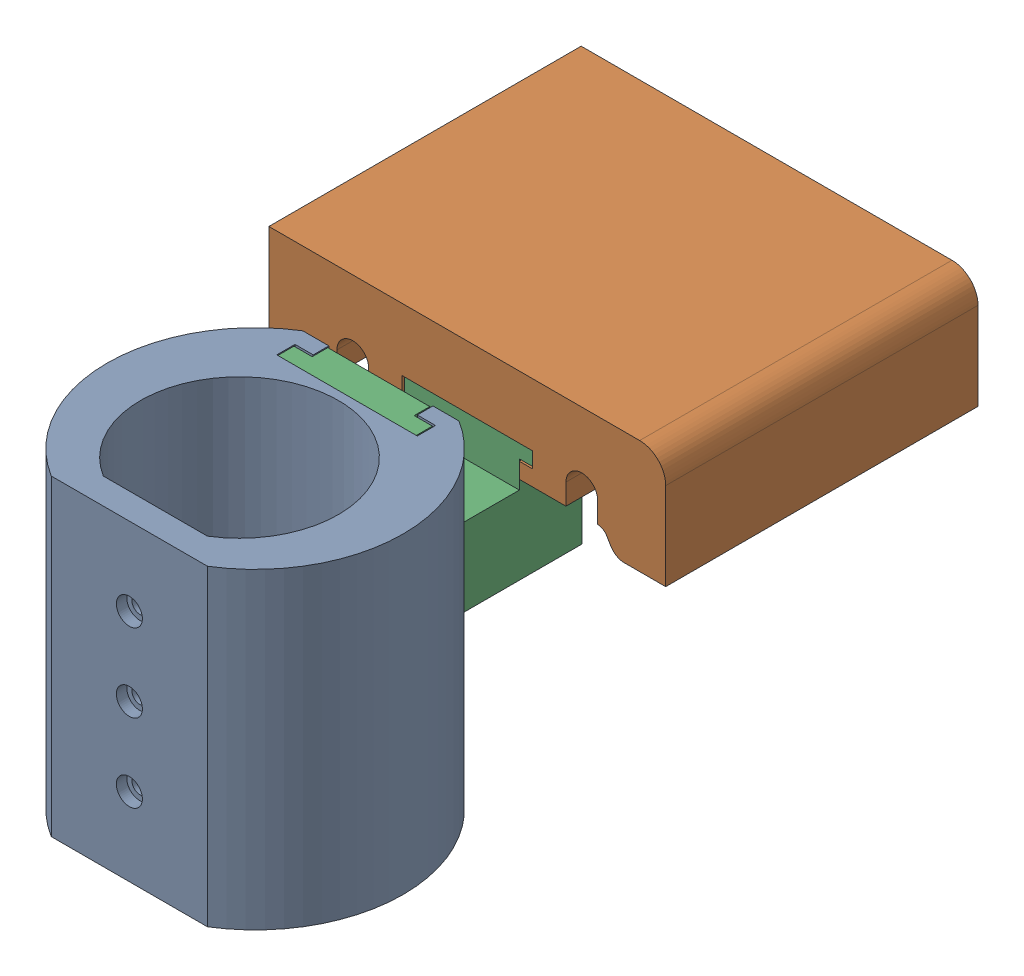
SolidWorks assembly zeiss_multipart, configuration Default. Lengths in mm.
Overall size (76.24 60 125.12).
3 component instances, 3 part files, 6 mates.
Components (placement in the parent):
- zeiss_mount_bracket_1-1: zeiss_mount_bracket_1 [Default] at origin size (56.88 60 48.32)
- zeiss_mount_bracket_2-1: zeiss_mount_bracket_2 [Modified bracket] at (-0.2 9.3 -103.9614) x (-1 0 0) z (0 -1 0) size (76.24 60 21.82)
- zeiss_mount_bracket_3-1: zeiss_mount_bracket_3 [Default] at (0 0 -55.9614) x (0 0 -1) z (1 0 0) size (43.3 50 26.6)
Mates (geometry in assembly coordinates):
- Coincident8: coincident anti-aligned: plane of zeiss_mount_bracket_2-1 through (12.3 15.3 -63.9614) normal (0 -1 0); plane of zeiss_mount_bracket_3-1 through (0 15.3 -55.9614) normal (0 1 0)
- Coincident9: coincident anti-aligned: plane of zeiss_mount_bracket_2-1 through (12.3 12.3 -63.9614) normal (-1 0 0); plane of zeiss_mount_bracket_3-1 through (12.3 15.5 -63.9614) normal (1 0 0)
- Coincident10: coincident anti-aligned: plane of zeiss_mount_bracket_2-1 through (-0.2 9.3 -63.9614) normal (0 0 1); plane of zeiss_mount_bracket_3-1 through (12.5 15.5 -63.9614) normal (0 0 -1)
- Coincident13: coincident anti-aligned: plane of zeiss_mount_bracket_1-1 through (0 -20 -3) normal (0 1 0); plane of zeiss_mount_bracket_3-1 through (0 -20 -55.9614) normal (0 -1 0)
- Coincident14: coincident: point of zeiss_mount_bracket_1-1; unknown of zeiss_mount_bracket_3-1
- Coincident15: coincident anti-aligned: plane of zeiss_mount_bracket_1-1 through (-13.5 -57.7714 -20.6614) normal (0 0 -1); plane of zeiss_mount_bracket_3-1 through (-13.5 -20 -20.6614) normal (0 0 1)
